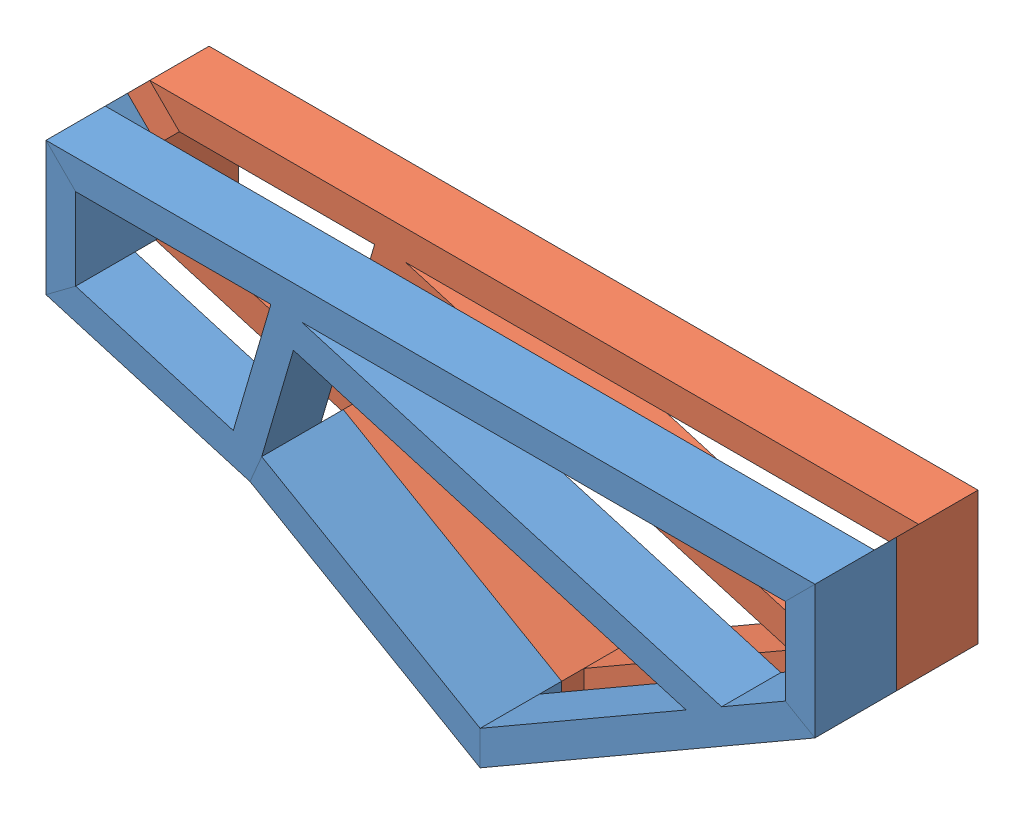
SolidWorks assembly Сборка4, configuration По умолчанию. Lengths in mm.
Overall size (1037.57 440.47 220).
2 component instances, 2 part files, 1 mates.
Components (placement in the parent):
- Electrokukel(Рама L)-1: Electrokukel(Рама L) [По умолчанию] at (-506.4409 199.3918 14.4482) size (1037.57 440.47 110)
- Electrokukel(Рама R)-1: Electrokukel(Рама R) [По умолчанию] at (-506.4409 199.3918 -125.5518) size (1037.57 440.47 110)
Mates (geometry in assembly coordinates):
- Совпадение1: coincident: point of Electrokukel(Рама L)-1; point of Electrokukel(Рама R)-1
